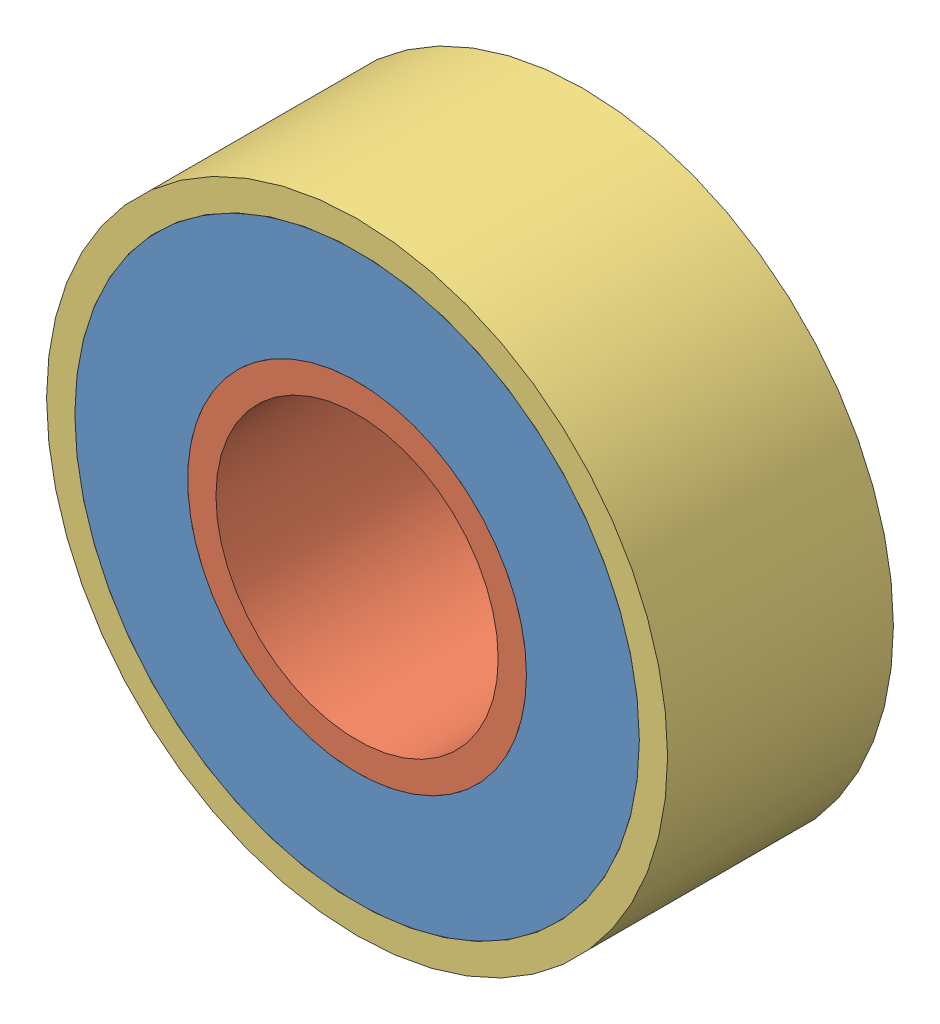
SolidWorks assembly Rolamento_5mm, configuration Valor predeterminado. Lengths in mm.
Overall size (11 11 4).
3 component instances, 3 part files, 0 mates.
Components (placement in the parent):
- 5MM_BEARING_COVER-1: 5MM_BEARING_COVER [Valor predeterminado] at (-549.475 -32.5 9.525) x (1 0 0) z (0 0 -1) size (10 10 4)
- 5MM_BEARING_INNER_RACE-1: 5MM_BEARING_INNER_RACE [Valor predeterminado] at (-549.475 -32.5 5.525) size (6 6 4)
- 5MM_BEARING_OUTER_RACE-1: 5MM_BEARING_OUTER_RACE [Valor predeterminado] at (-549.475 -32.5 5.525) size (11 11 4)
